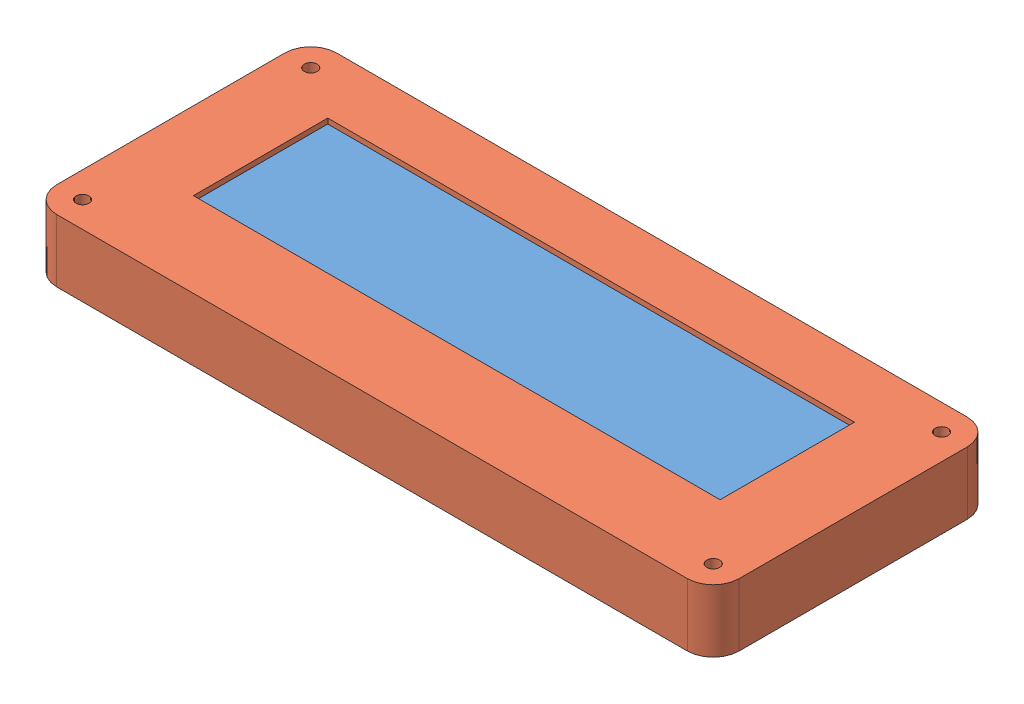
SolidWorks assembly LCD assembly, configuration Default. Lengths in mm.
Overall size (132.15 12.15 54.2).
2 component instances, 2 part files, 0 mates.
Components (placement in the parent):
- LCD-1: LCD [Default] at (-11.3148 68.4651 120.5842) size (122.15 10.65 44.2)
- LCD Housing-1: LCD Housing [Default] at origin size (132.15 12.15 54.2)
